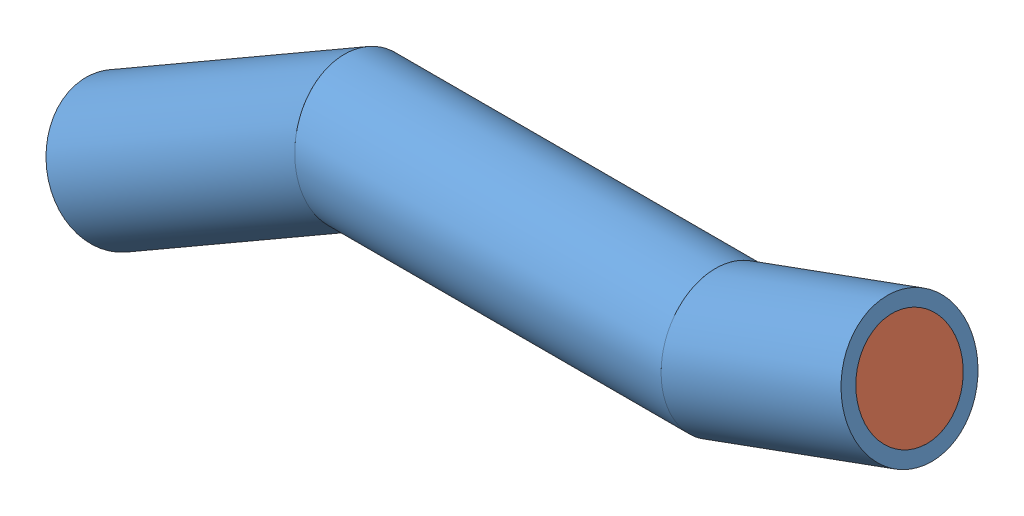
SolidWorks assembly Ensamblaje4, configuration Predeterminado. Lengths in mm.
Overall size (138.97 53.24 21.3).
3 component instances, 3 part files, 0 mates.
Components (placement in the parent):
- Pieza3-1: Pieza3 [Predeterminado<Como mecanizada>] at (-77.4912 -6.8923 138.9675) size (138.97 53.24 21.3)
- LID3-1: LID3 [Predeterminado] at origin size (6.59 16.4 17.18)
- LID4-1: LID4 [Predeterminado] at origin size (9.25 15.26 17.18)
